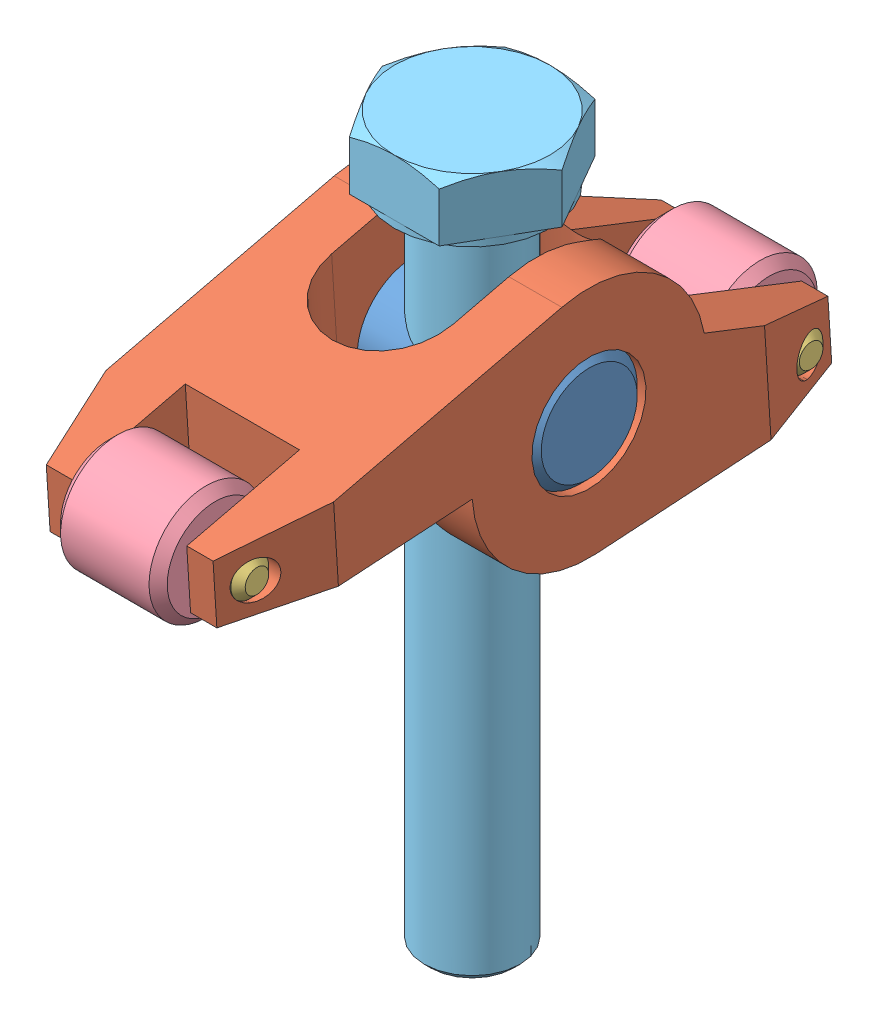
SolidWorks assembly Rocker Arm Assembly B, configuration Predeterminado. Lengths in mm.
Overall size (19.05 60.3 55.78).
7 component instances, 5 part files, 12 mates.
Components (placement in the parent):
- Rocker Arm Pin 1-1: Rocker Arm Pin 1 [Predeterminado] at origin size (19.05 9.53 9.53)
- Rocker Arm-1: Rocker Arm [Predeterminado] x (1 0 0) z (0 0.063662 -0.997972) size (19 19.53 50.8)
- Rocker Arm Pin 2-1: Rocker Arm Pin 2 [Predeterminado] at (0 0.8774 26.1439) x (0 -0.991183 -0.132503) z (0 -0.132503 0.991183) size (3.17 15.87 3.17)
- Rocker Arm Roll-1: Rocker Arm Roll [Predeterminado] at (0 -5.9572 -20.105) size (8.9 9.53 9.53)
- Rocker Arm Roll-2: Rocker Arm Roll [Predeterminado] at (0 0.8774 26.1439) size (8.9 9.53 9.53)
- Rocker Arm Pin 2-2: Rocker Arm Pin 2 [Predeterminado] at (0 -5.9572 -20.105) x (0 -0.997287 0.073613) z (0 0.073613 0.997287) size (3.17 15.87 3.17)
- hex screw gradeab fine_iso-3: hex screw gradeab fine_iso [ISO 8676 - M8x1.0 x 55-N] at (0 18 0.25) x (0 -1 0) z (0 0 1) size (60.3 15.01 13)
Mates (geometry in assembly coordinates):
- Concéntrica1: concentric aligned: cylinder of Rocker Arm Pin 1-1 through (9.525 0 0) axis (-1 0 0) radius 4.765; cylinder of Rocker Arm-1 through (9.5 0 0) axis (-1 0 0) radius 4.765
- Ancho1: width anti-aligned: plane of Rocker Arm Pin 1-1 through (9.525 0 0) normal (1 0 0); plane of Rocker Arm Pin 1-1 through (-9.525 0 0) normal (-1 0 0); plane of Rocker Arm-1 through (-9.5 0 0) normal (-1 0 0); plane of Rocker Arm-1 through (9.5 0 0) normal (1 0 0)
- Concéntrica2: concentric anti-aligned: cylinder of Rocker Arm-1 through (-9.5 -5.9572 -20.105) axis (1 0 0) radius 1.59; cylinder of Rocker Arm Roll-1 through (4.45 -5.9572 -20.105) axis (-1 0 0) radius 4.765
- Ancho2: width anti-aligned: plane of Rocker Arm Roll-1 through (-4.45 -5.9572 -20.105) normal (-1 0 0); plane of Rocker Arm Roll-1 through (4.45 -5.9572 -20.105) normal (1 0 0); plane of Rocker Arm-1 through (-4.765 10.5534 -12.0476) normal (1 0 0); plane of Rocker Arm-1 through (4.765 10.5534 -12.0476) normal (-1 0 0)
- Concéntrica3: concentric anti-aligned: cylinder of Rocker Arm-1 through (-9.5 0.8774 26.1439) axis (1 0 0) radius 1.59; cylinder of Rocker Arm Roll-2 through (4.45 0.8774 26.1439) axis (-1 0 0) radius 4.765
- Ancho3: width aligned: plane of Rocker Arm Roll-2 through (4.45 0.8774 26.1439) normal (1 0 0); plane of Rocker Arm Roll-2 through (-4.45 0.8774 26.1439) normal (-1 0 0); plane of Rocker Arm-1 through (-4.765 8.5327 19.628) normal (1 0 0); plane of Rocker Arm-1 through (4.765 8.5327 19.628) normal (-1 0 0)
- Concéntrica4: concentric anti-aligned: cylinder of Rocker Arm-1 through (-9.5 0.8774 26.1439) axis (1 0 0) radius 1.59; cylinder of Rocker Arm Pin 2-1 through (7.935 0.8774 26.1439) axis (-1 0 0) radius 1.585
- Concéntrica5: concentric anti-aligned: cylinder of Rocker Arm-1 through (-9.5 -5.9572 -20.105) axis (1 0 0) radius 1.59; cylinder of Rocker Arm Pin 2-2 through (7.935 -5.9572 -20.105) axis (-1 0 0) radius 1.585
- Ancho4: width aligned: plane of Rocker Arm Pin 2-1 through (-7.935 0.8774 26.1439) normal (-1 0 0); plane of Rocker Arm Pin 2-1 through (7.935 0.8774 26.1439) normal (1 0 0); plane of Rocker Arm-1 through (4.765 8.5327 19.628) normal (-1 0 0); plane of Rocker Arm-1 through (-4.765 8.5327 19.628) normal (1 0 0)
- Ancho5: width aligned: plane of Rocker Arm Pin 2-2 through (7.935 -5.9572 -20.105) normal (1 0 0); plane of Rocker Arm Pin 2-2 through (-7.935 -5.9572 -20.105) normal (-1 0 0); plane of Rocker Arm-1 through (-4.765 10.5534 -12.0476) normal (1 0 0); plane of Rocker Arm-1 through (4.765 10.5534 -12.0476) normal (-1 0 0)
- Concéntrica8: concentric aligned: cylinder of Rocker Arm Pin 1-1 through (0 -4.765 0.25) axis (0 1 0) radius 3.43; cylinder of hex screw gradeab fine_iso-3 through (0 18 0.25) axis (0 1 0) radius 6.5
- Distancia1: distance = 12.7 mm anti-aligned: plane of Rocker Arm Pin 1-1 through (0 0 0) normal (0 1 0); plane of hex screw gradeab fine_iso-3 through (7.5056 12.7 0.25) normal (0 -1 0)
